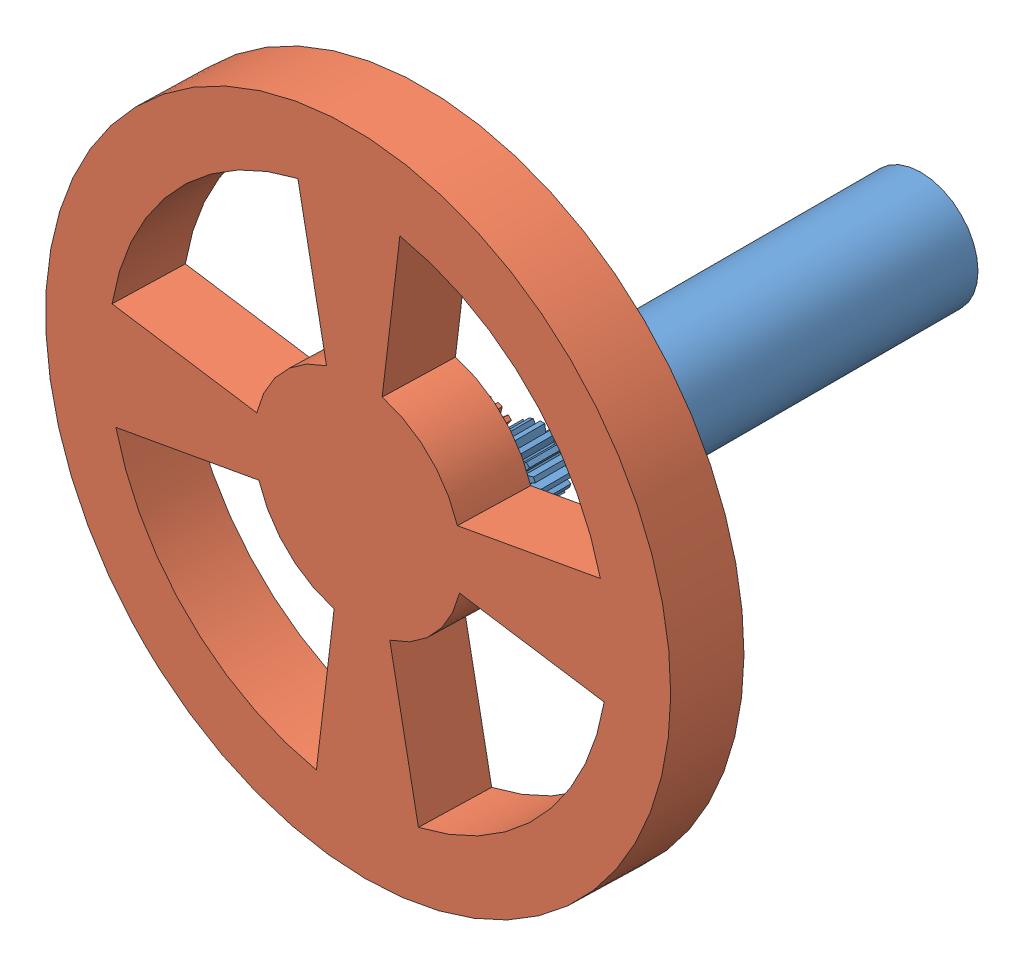
SolidWorks assembly Montagem1, configuration Valor predeterminado. Lengths in mm.
Overall size (127.62 127.2 72.17).
2 component instances, 2 part files, 0 mates.
Components (placement in the parent):
- Motor1.1-1: Motor1.1 [Valor predeterminado] at (3.4549 0.5651 59) size (16 16 59)
- Roda-1: Roda [Valor predeterminado] at (-4.8935 -0.4877 129.4765) x (-0.678644 -0.734266 -0.017193) z (0.026677 -0.001249 -0.999643) size (90 90 18)
